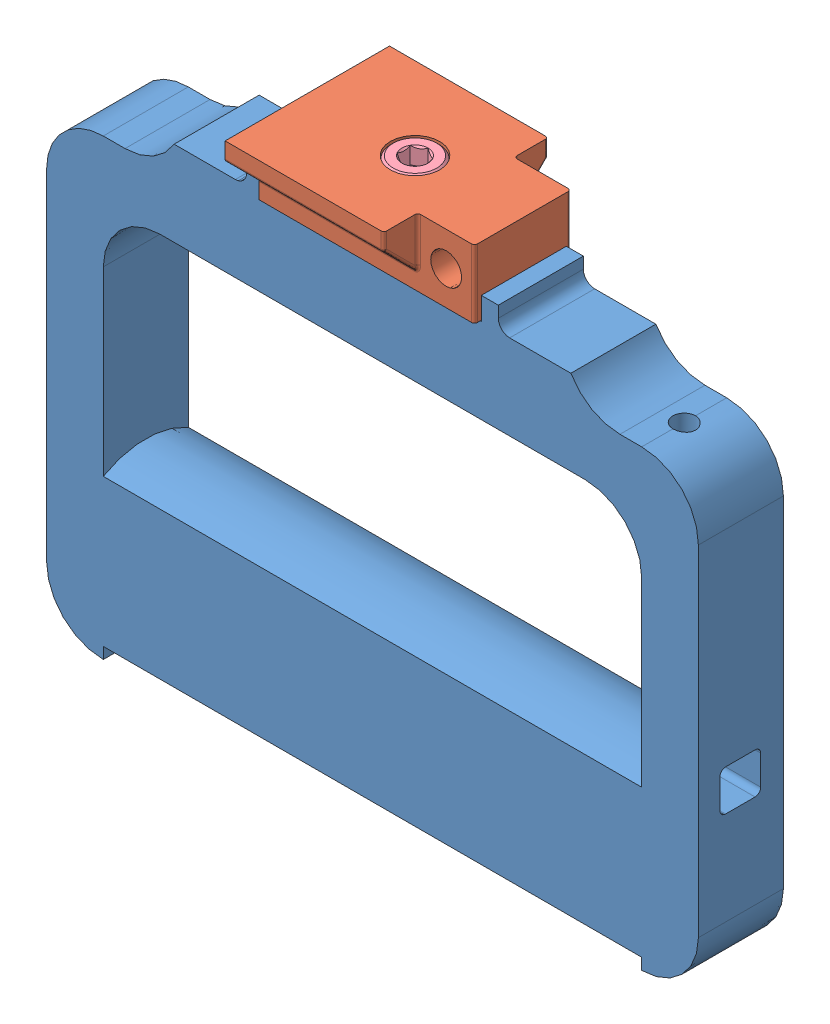
SolidWorks assembly RobotHandExtensionAssembly, configuration Default. Lengths in mm.
Overall size (115 97.23 29).
4 component instances, 4 part files, 9 mates.
Components (placement in the parent):
- RobotHandExtension-1: RobotHandExtension [Default] at (-75.1219 83.5916 -31.6631) x (0 -1 0) z (0 0 1) size (89 115 15)
- dovetail_male_RobotHandExtension-1: dovetail_male_RobotHandExtension [Default] at (-17.6219 88.5916 -24.1631) x (0 0 1) z (-1 0 0) size (29 12 38)
- 91828A241 - NutM5-1: 91828A241 - NutM5 [91828A241] at (-17.6219 77.5916 -24.1631) x (0 0 -1) z (0 1 0) size (8 9.24 4.46)
- 92290A782 - ScrewM5L22-1: 92290A782 - ScrewM5L22 [92290A782] at (-17.6219 73.5916 -24.1631) x (1 0 0) z (0 -1 0) size (8.5 8.5 27.93)
Mates (geometry in assembly coordinates):
- Parallel1: parallel anti-aligned: plane of dovetail_male_RobotHandExtension-1 through (-36.6219 88.5916 -32.6631) normal (0 -1 0); plane of RobotHandExtension-1 through (17.3781 88.5916 -16.6631) normal (0 1 0)
- Parallel2: parallel anti-aligned: plane of RobotHandExtension-1 through (-75.1219 83.5916 -16.6631) normal (0 0 1); plane of dovetail_male_RobotHandExtension-1 through (-36.6219 91.5916 -32.6631) normal (0 0 -1)
- Coincident1: coincident anti-aligned: plane of RobotHandExtension-1 through (17.3781 88.5916 -16.6631) normal (0 1 0); plane of dovetail_male_RobotHandExtension-1 through (-36.6219 88.5916 -32.6631) normal (0 -1 0)
- Concentric1: concentric anti-aligned: cylinder of RobotHandExtension-1 through (-17.6219 3.5906 -24.1631) axis (0 1 0) radius 2.725; cylinder of dovetail_male_RobotHandExtension-1 through (-17.6219 100.5916 -24.1631) axis (0 -1 0) radius 2.725
- Concentric2: concentric anti-aligned: circle of RobotHandExtension-1; circle of 91828A241 - NutM5-1
- Coincident2: coincident anti-aligned: plane of RobotHandExtension-1 through (-75.1219 79.5916 -31.6631) normal (0 -1 0); plane of 91828A241 - NutM5-1 through (-19.9313 79.5916 -20.1631) normal (0 1 0)
- Parallel3: parallel anti-aligned: plane of RobotHandExtension-1 through (-15.2547 79.5916 -20.0631) normal (0 0 -1); plane of 91828A241 - NutM5-1 through (-19.9313 79.5916 -20.1631) normal (0 0 1)
- Concentric4: concentric anti-aligned: circle of dovetail_male_RobotHandExtension-1; circle of 92290A782 - ScrewM5L22-1
- Coincident5: coincident anti-aligned: plane of dovetail_male_RobotHandExtension-1 through (-17.6219 95.5916 -24.1631) normal (0 1 0); plane of 92290A782 - ScrewM5L22-1 through (-17.6219 95.5916 -24.1631) normal (0 -1 0)
